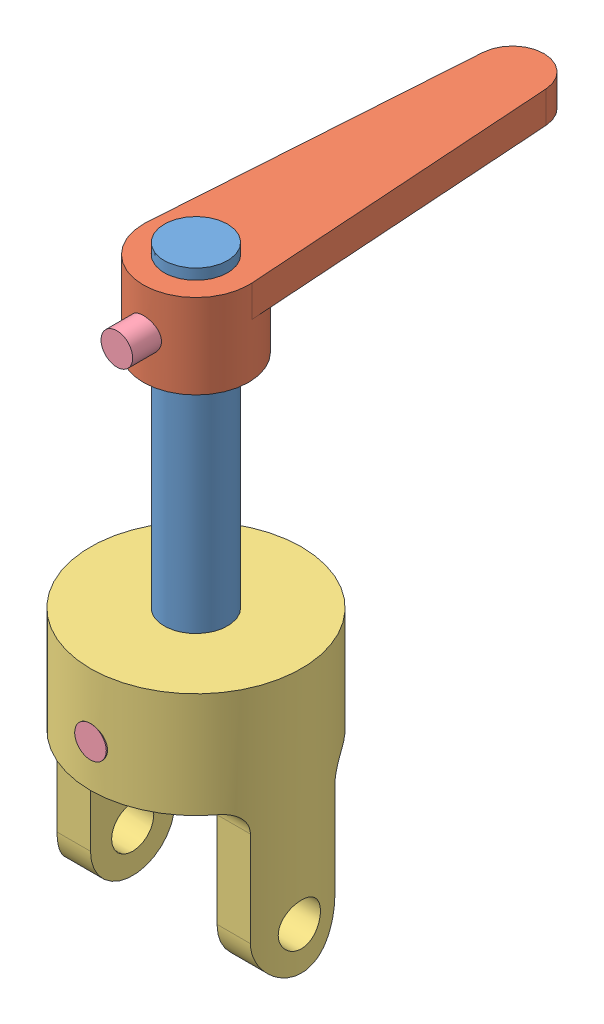
SolidWorks assembly 110303047-92, configuration 預設. Lengths in mm.
Overall size (20 55 43).
5 component instances, 4 part files, 8 mates.
Components (placement in the parent):
- Part-4-1: Part-4 [預設] at (-3.8203 -6.2081 40) x (-1 0 0) z (0 0 1) size (6 40 6)
- Part-5-1: Part-5 [預設] at (-3.8203 9.7919 40) x (0 0 -1) z (1 0 0) size (38 8 10)
- Part-6-1: Part-6 [預設] at (-3.8203 -16.2081 40) x (-1 0 0) z (0 0 1) size (20 25 20)
- Part-7-1: Part-7 [預設] at (-3.8203 -22.2081 45) x (0 0 -1) z (-0.988105 0.153783 0) size (10 3 3)
- Part-7-2: Part-7 [預設] at (-3.8203 8.7919 42.5) x (0 0 -1) z (0.999497 -0.031702 0) size (10 3 3)
Mates (geometry in assembly coordinates):
- 同軸心1: concentric anti-aligned: cylinder of 110303047-94-1 through (-3.8203 8.7919 37) axis (0 0 1) radius 1.5; cylinder of 110303047-95-1 through (-3.8203 8.7919 45) axis (0 0 -1) radius 1.5
- 同軸心2: concentric anti-aligned: cylinder of 110303047-94-1 through (-3.8203 -26.2081 40) axis (0 1 0) radius 3; cylinder of 110303047-95-1 through (-3.8203 12.7919 40) axis (0 -1 0) radius 3
- 同軸心3: concentric aligned: cylinder of 110303047-94-1 through (-3.8203 -26.2081 40) axis (0 1 0) radius 3; cylinder of 110303047-96-1 through (-3.8203 -41.2081 40) axis (0 1 0) radius 3
- 同軸心4: concentric anti-aligned: cylinder of 110303047-94-1 through (-3.8203 -22.2081 37) axis (0 0 1) radius 1.5; cylinder of 110303047-96-1 through (-3.8203 -22.2081 50) axis (0 0 -1) radius 1.5
- 同軸心6: concentric: cylinder of 110303047-95-1 through (-3.8203 8.7919 45) axis (0 0 -1) radius 1.5; cylinder of 110303047-97-2 through (-3.8203 8.7919 37.5622) axis (0 0 1) radius 1.5
- 同軸心7: concentric: cylinder of 110303047-96-1 through (-3.8203 -22.2081 50) axis (0 0 -1) radius 1.5; cylinder of 110303047-97-1 through (-3.8203 -22.2081 40) axis (0 0 1) radius 1.5
- 相切2: tangent aligned: cylinder of 110303047-96-1 through (-3.8203 -41.2081 40) axis (0 1 0) radius 10; plane of 110303047-97-1 through (-3.8203 -22.2081 50) normal (0 0 1)
- 平行相距1: distance = 7.5 mm: cylinder of 110303047-95-1 through (-3.8203 12.7919 40) axis (0 -1 0) radius 5; plane of 110303047-97-2 through (-3.8203 8.7919 47.5) normal (0 0 1)
